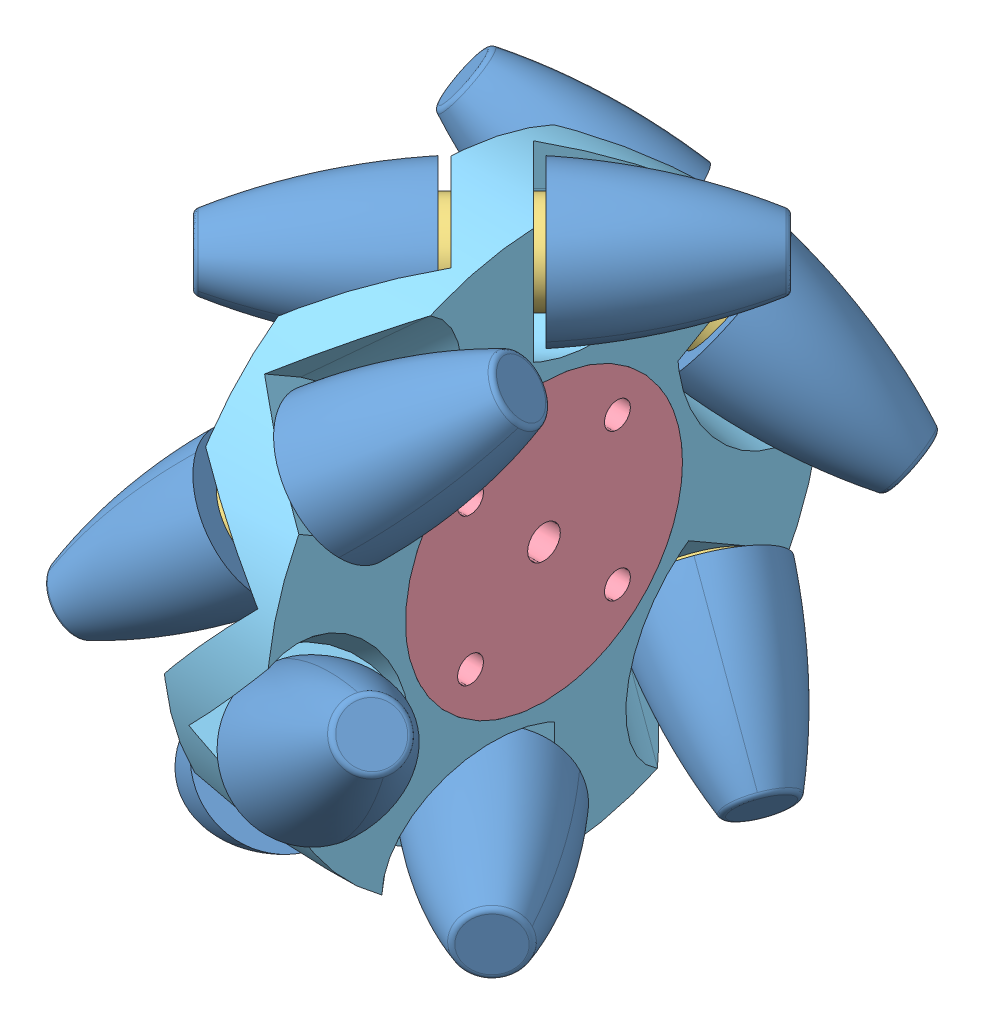
SolidWorks assembly Mecanum Wheel A, configuration Valor predeterminado. Lengths in mm.
Overall size (40.43 59.23 66.47).
32 component instances, 5 part files, 0 mates.
Components (placement in the parent):
- rubber roller-1: rubber roller [Valor predeterminado] at (-22.1009 9.2708 53.4652) x (0.707107 0 -0.707107) z (0.389805 0.834329 0.389805) size (15.88 13.22 13.13)
- rubber roller-2: rubber roller [Valor predeterminado] at (-22.1014 1.0874 72.5712) x (0.707107 0.612372 -0.353553) z (0.253872 -0.686523 -0.681348) size (15.88 13.22 13.13)
- rubber roller-3: rubber roller [Valor predeterminado] at (-22.1014 -19.5501 75.0369) x (0.707107 0.612372 0.353553) z (-0.391226 -0.077687 0.91701) size (15.88 13.22 13.13)
- rubber roller-4: rubber roller [Valor predeterminado] at (-22.1014 -32.0042 58.3971) x (0.707107 0 0.707107) z (-0.29752 0.907173 0.29752) size (15.88 13.22 13.13)
- rubber roller-5: rubber roller [Valor predeterminado] at (-22.1009 -3.1838 36.8257) x (0.707107 -0.612372 -0.353553) z (0.69392 0.504841 0.51343) size (15.88 13.22 13.13)
- rubber roller-6: rubber roller [Valor predeterminado] at (-22.1014 -23.8208 39.2917) x (0.707107 -0.612372 0.353553) z (-0.5772 -0.211044 0.788861) size (15.88 13.22 13.13)
- rubber roller-7: rubber roller [Valor predeterminado] at (-27.0334 -23.8213 72.5709) x (-0.707107 -0.612372 -0.353553) z (-0.685872 0.47237 0.553576) size (15.88 13.22 13.13)
- rubber roller-8: rubber roller [Valor predeterminado] at (-27.0334 -32.0042 53.4652) x (-0.707107 0 -0.707107) z (0.707107 0 -0.707107) size (15.88 13.22 13.13)
- rubber roller-9: rubber roller [Valor predeterminado] at (-27.0334 -19.5496 36.8257) x (-0.707107 0.612372 -0.353553) z (0.622049 0.300954 -0.722829) size (15.88 13.22 13.13)
- rubber roller-10: rubber roller [Valor predeterminado] at (-27.0334 -3.1838 75.0371) x (-0.707107 -0.612372 0.353553) z (-0.548605 0.159643 -0.820699) size (15.88 13.22 13.13)
- rubber roller-11: rubber roller [Valor predeterminado] at (-27.0328 1.0874 39.2917) x (-0.707107 0.612372 0.353553) z (0.670094 0.420673 0.611562) size (15.88 13.22 13.13)
- rubber roller-12: rubber roller [Valor predeterminado] at (-27.0328 9.2708 58.3971) x (-0.707107 0 0.707107) z (-0.318668 -0.892693 -0.318668) size (15.88 13.22 13.13)
- steel pin-1: steel pin [Valor predeterminado] at (-36.0131 9.2708 67.3774) x (0.707107 0 -0.707107) z (-0.417696 -0.806883 -0.417696) size (32.38 3.18 3.18)
- steel pin-2: steel pin [Valor predeterminado] at (-36.0136 -10.9609 79.5273) x (0.707107 0.612372 -0.353553) z (0.662238 -0.748788 0.027538) size (32.38 3.18 3.18)
- steel pin-3: steel pin [Valor predeterminado] at (-36.0136 -31.5984 68.0808) x (0.707107 0.612372 0.353553) z (0.672023 -0.426449 -0.605414) size (32.38 3.18 3.18)
- steel pin-4: steel pin [Valor predeterminado] at (-36.0136 -32.0042 44.4849) x (0.707107 0 0.707107) z (-0.643237 0.415323 0.643237) size (32.38 3.18 3.18)
- steel pin-5: steel pin [Valor predeterminado] at (-36.0136 -11.7725 32.3356) x (0.707107 -0.612372 0.353553) z (0.683232 0.720526 -0.118476) size (32.38 3.18 3.18)
- steel pin-6: steel pin [Valor predeterminado] at (-36.0131 8.8646 43.7818) x (0.707107 -0.612372 -0.353553) z (-0.168488 -0.631514 0.756837) size (32.38 3.18 3.18)
- Flat Washer Type A Narrow_AI_FW 0.125-1: Flat Washer Type A Narrow_AI_FW 0.125 [Valor predeterminado] at (-26.4586 9.2708 57.8229) x (0.707107 0 -0.707107) z (0.707107 0 0.707107) size (0.81 7.92 7.92)
- Flat Washer Type A Narrow_AI_FW 0.125-2: Flat Washer Type A Narrow_AI_FW 0.125 [Valor predeterminado] at (-26.4586 0.5902 39.0046) x (0.707107 -0.612372 -0.353553) z (0.353553 -0.126826 0.926777) size (0.81 7.92 7.92)
- Flat Washer Type A Narrow_AI_FW 0.125-3: Flat Washer Type A Narrow_AI_FW 0.125 [Valor predeterminado] at (-26.4586 -20.0473 37.1131) x (0.707107 -0.612372 0.353553) z (-0.353553 0.126826 0.926777) size (0.81 7.92 7.92)
- Flat Washer Type A Narrow_AI_FW 0.125-4: Flat Washer Type A Narrow_AI_FW 0.125 [Valor predeterminado] at (-26.4586 -32.0042 54.0399) x (0.707107 0 0.707107) z (-0.707107 0 0.707107) size (0.81 7.92 7.92)
- Flat Washer Type A Narrow_AI_FW 0.125-5: Flat Washer Type A Narrow_AI_FW 0.125 [Valor predeterminado] at (-26.4586 -23.3235 72.8583) x (0.707107 0.612372 0.353553) z (-0.353553 -0.126826 0.926777) size (0.81 7.92 7.92)
- Flat Washer Type A Narrow_AI_FW 0.125-6: Flat Washer Type A Narrow_AI_FW 0.125 [Valor predeterminado] at (-26.4586 -2.686 74.7498) x (0.707107 0.612372 -0.353553) z (0.353553 0.126826 0.926777) size (0.81 7.92 7.92)
- Flat Washer Type A Narrow_AI_FW 0.125-7: Flat Washer Type A Narrow_AI_FW 0.125 [Valor predeterminado] at (-22.6756 -2.686 37.1131) x (-0.707107 0.612372 0.353553) z (0.532501 0.13219 0.836043) size (0.81 7.92 7.92)
- Flat Washer Type A Narrow_AI_FW 0.125-8: Flat Washer Type A Narrow_AI_FW 0.125 [Valor predeterminado] at (-22.6756 9.2708 54.0399) x (-0.707107 0 0.707107) z (-0.707107 0 -0.707107) size (0.81 7.92 7.92)
- Flat Washer Type A Narrow_AI_FW 0.125-9: Flat Washer Type A Narrow_AI_FW 0.125 [Valor predeterminado] at (-22.6756 0.5902 72.8583) x (-0.707107 -0.612372 0.353553) z (-0.353553 0.739199 0.573223) size (0.81 7.92 7.92)
- Flat Washer Type A Narrow_AI_FW 0.125-10: Flat Washer Type A Narrow_AI_FW 0.125 [Valor predeterminado] at (-22.6756 -23.3235 39.0046) x (-0.707107 0.612372 -0.353553) z (0.353553 0.739199 0.573223) size (0.81 7.92 7.92)
- Flat Washer Type A Narrow_AI_FW 0.125-11: Flat Washer Type A Narrow_AI_FW 0.125 [Valor predeterminado] at (-22.6756 -32.0042 57.8229) x (-0.707107 0 -0.707107) z (0.707107 0 -0.707107) size (0.81 7.92 7.92)
- Flat Washer Type A Narrow_AI_FW 0.125-12: Flat Washer Type A Narrow_AI_FW 0.125 [Valor predeterminado] at (-22.6756 -20.0473 74.7498) x (-0.707107 -0.612372 -0.353553) z (0.353553 -0.739199 0.573223) size (0.81 7.92 7.92)
- Mecanum mount R2-1: Mecanum mount R2 [Valor predeterminado] at (-22.9796 -11.3667 55.9314) size (9.53 25.4 25.4)
- Mecanum Hub A R2-1: Mecanum Hub A R2 [Valor predeterminado] at (-24.5671 -11.3667 55.9314) size (9.53 50.8 50.8)
